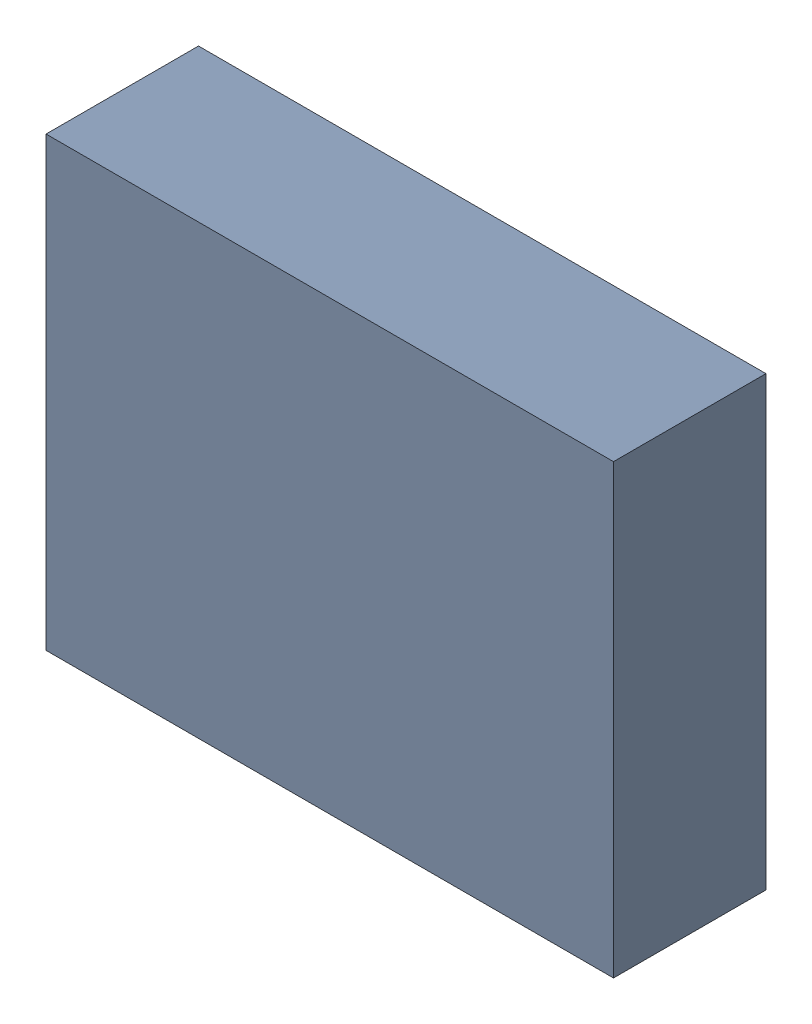
SolidWorks assembly R2, configuration Default. Lengths in mm.
Overall size (3.35 2.64 0.9).
2 component instances, 1 part files, 0 mates.
Components (placement in the parent):
- 5920132160-1: 5920132160 [Default] at (37.5 44.25 0) size (3.35 2.64 0.9)
  - Extruded-1: Extruded [Default] at origin size (3.35 2.64 0.9)
